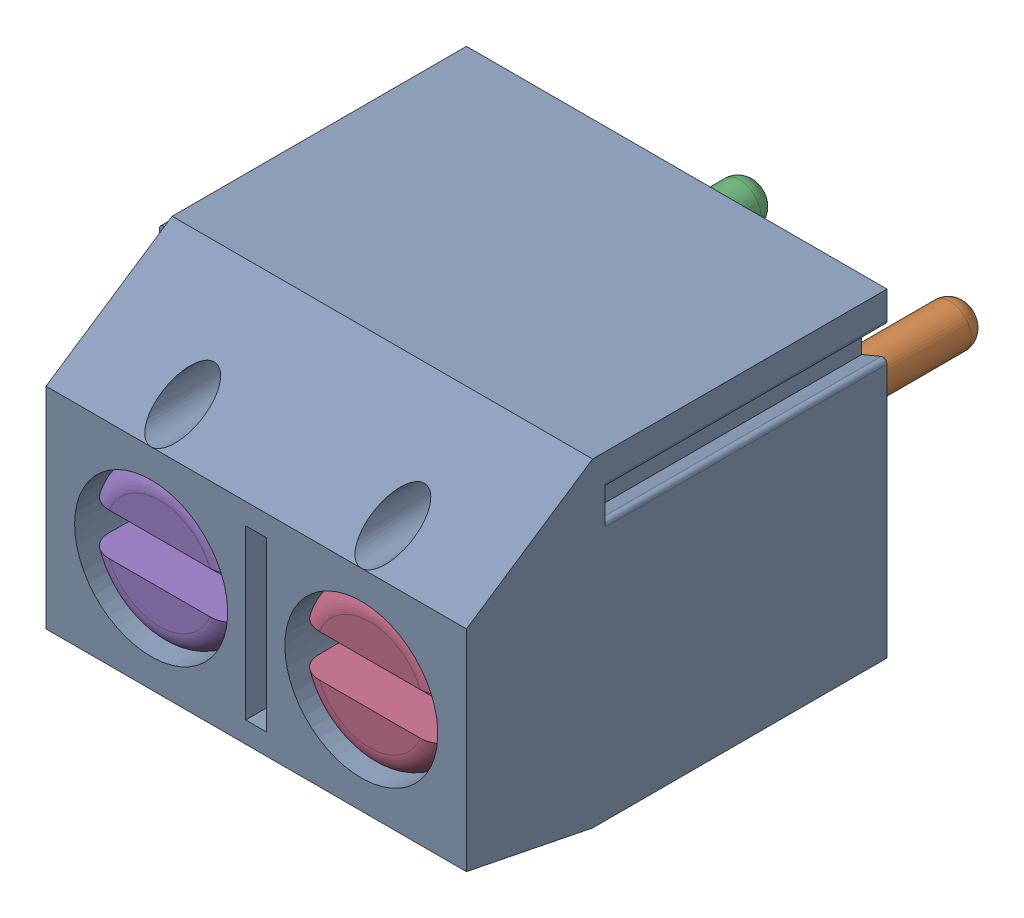
SolidWorks assembly DG301-5.0-02 (OPTION 1)-3, configuration Default. Lengths in mm.
Overall size (10.6 7.6 14.4).
7 component instances, 4 part files, 0 mates.
Components (placement in the parent):
- DG301-5.0-02-body-1: DG301-5.0-02-body [Default] at origin size (10.6 7.6 10)
- DG301-5.0-pin-1: DG301-5.0-pin [Default] at (5 0.5 2.85) size (3.9 4 9.9)
- DG301-5.0-pin-2: DG301-5.0-pin [Default] at (0 0.5 2.85) size (3.9 4 9.9)
- DG301-5.0-screw-1: DG301-5.0-screw [Default] at (5 0 4) size (3.6 3.6 5.84)
- DG301-5.0-screw-2: DG301-5.0-screw [Default] at (0 0 4) size (3.6 3.6 5.84)
- DG301-5.0-wire_prot-1: DG301-5.0-wire_prot [Default] at (5 0 5.5) size (3.9 5.45 2.85)
- DG301-5.0-wire_prot-2: DG301-5.0-wire_prot [Default] at (0 0 5.5) size (3.9 5.45 2.85)
